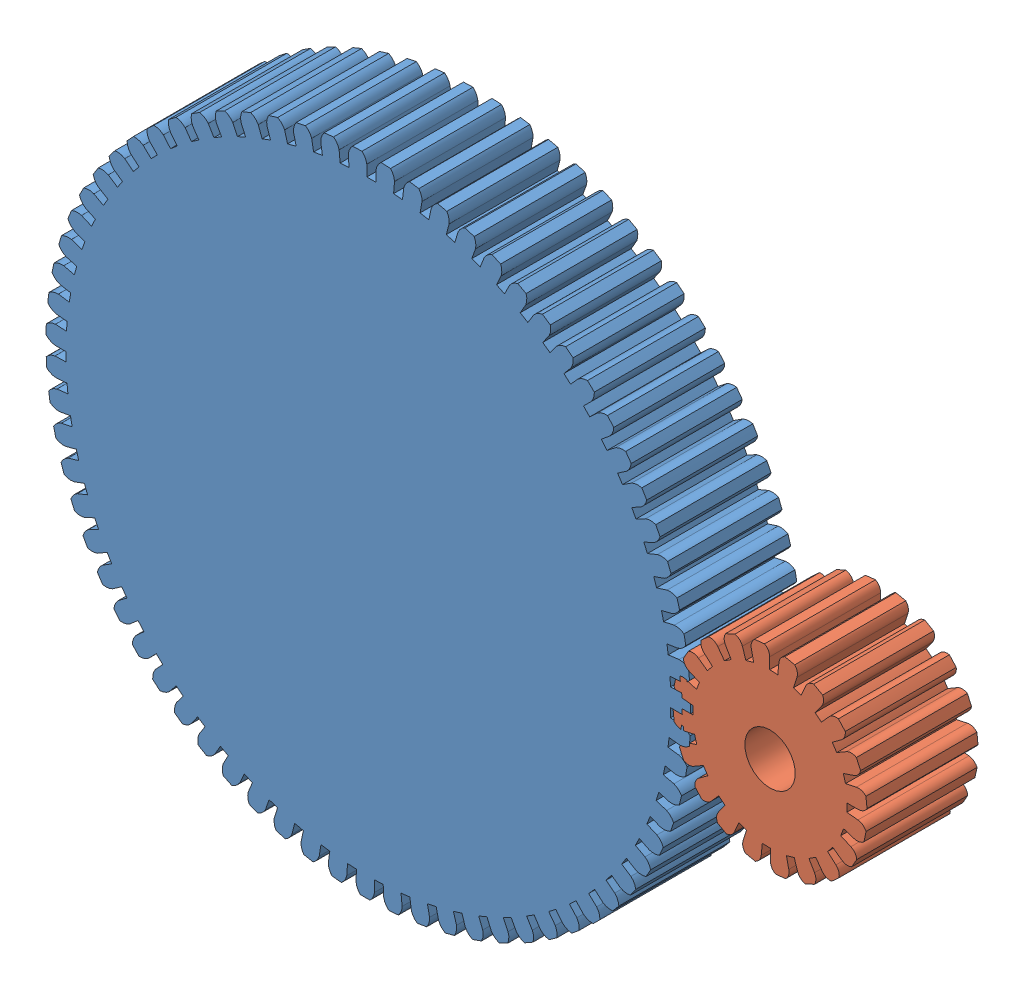
SolidWorks assembly Assem2, configuration Default. Lengths in mm.
Overall size (353.36 279.41 44).
2 component instances, 2 part files, 6 mates.
Components (placement in the parent):
- Gear1-2: Gear1 [Default] at (-159.25 0 0) x (-0.098204 -0.995166 0) z (0 0 1) size (255.54 255.59 44)
- Gear2-2: Gear2 [Default] x (0.67241 -0.740179 0) z (0 0 1) size (77 77 44)
Mates (geometry in assembly coordinates):
- Coincident2: coincident aligned: plane of Gear1-2 through (-159.25 0 0) normal (0 0 1)
- Coincident3: coincident aligned: plane of Gear2-2 through (0 0 0) normal (0 0 1)
- Concentric1: concentric aligned: cylinder of Gear2-2 through (0 0 -22) axis (0 0 1) radius 10
- Distance1: distance = 159.25 mm: point of Gear1-2; point of Gear2-2
- Coincident5: coincident: point of Gear1-2; plane of assembly
- GearMate1: gear = 70 : 248.5 mm: circle of Gear1-2; circle of Gear2-2
